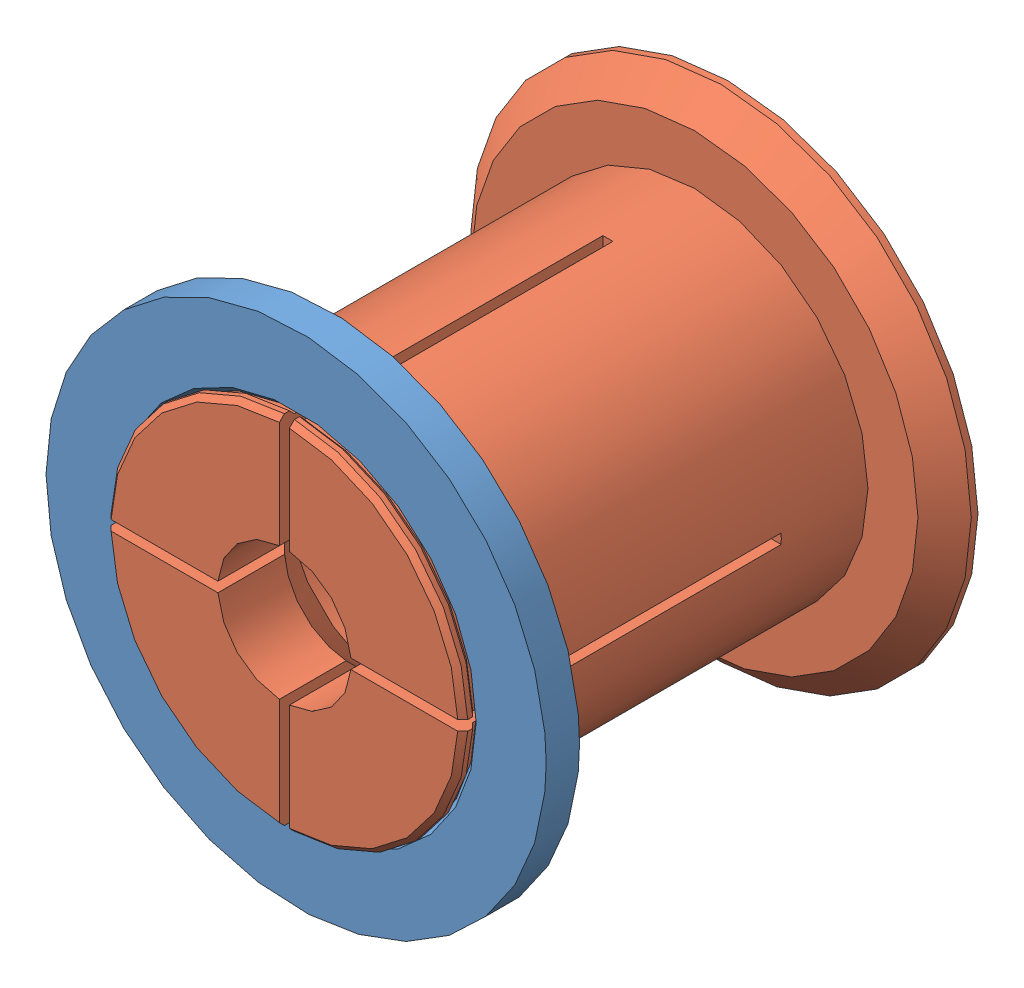
SolidWorks assembly Assem1, configuration Default. Lengths in mm.
Overall size (75 75 66.5).
2 component instances, 2 part files, 2 mates.
Components (placement in the parent):
- 53-55-20-spool-adapter-female-1: 53-55-20-spool-adapter-female [Default] at (17.1616 39.5812 60.4855) size (75 75 5)
- 53-55-20-spool-adapter-male-1: 53-55-20-spool-adapter-male [Default] at (17.1616 39.5812 5.7355) size (75 75 66.5)
Mates (geometry in assembly coordinates):
- Concentric1: concentric: cylinder of 53-55-20-spool-adapter-female-1 through (17.1616 39.5812 60.4855) axis (0 0 1) radius 26.25; cylinder of 53-55-20-spool-adapter-male-1 through (17.1616 39.5812 67.2355) axis (0 0 -1) radius 26
- Coincident1: coincident aligned: cone of 53-55-20-spool-adapter-female-1 through (17.1616 39.5812 61.2355) axis (0 0 1); cone of 53-55-20-spool-adapter-male-1 through (17.1616 39.5812 61.4855) axis (0 0 1)
